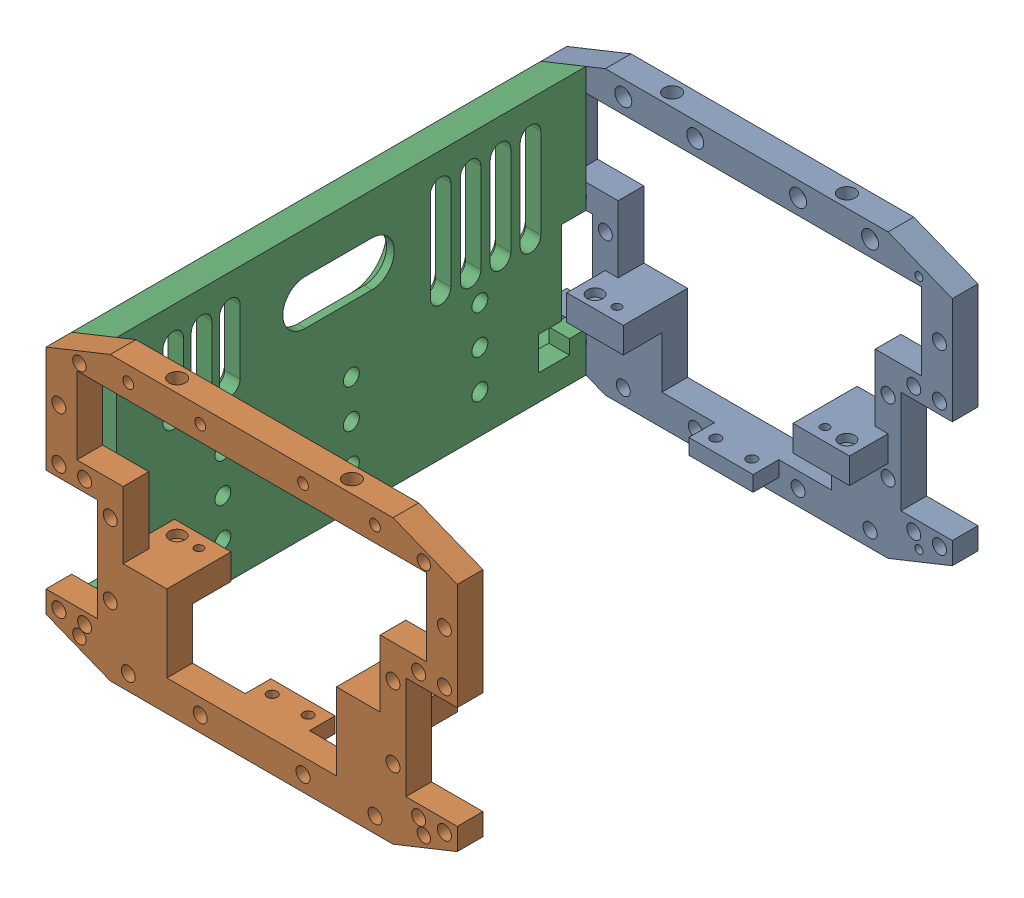
SolidWorks assembly BodyAssembly1, configuration Standard. Lengths in mm.
Overall size (160 110 202.6).
3 component instances, 2 part files, 6 mates.
Components (placement in the parent):
- BodyEnd-1: BodyEnd [Standard] at origin size (160 110 25)
- BodyEnd-2: BodyEnd [Standard] at (12.7503 0 202.6) x (-1 0 0) z (0 0 -1) size (160 110 25)
- SidePanel_Closed-1: SidePanel_Closed [Standard] at (-56.1248 4.9643 10) size (17.5 104 182.6)
Mates (geometry in assembly coordinates):
- Concentric1: concentric: circle of BodyEnd-1; circle of SidePanel_Closed-1
- Concentric2: concentric: circle of BodyEnd-1; circle of SidePanel_Closed-1
- Coincident1: coincident anti-aligned: plane of BodyEnd-1 through (61.3752 -50.0357 10) normal (0 0 1); plane of SidePanel_Closed-1 through (-56.1248 4.9643 10) normal (0 0 -1)
- Concentric3: concentric: circle of BodyEnd-2; circle of SidePanel_Closed-1
- Concentric4: concentric: circle of BodyEnd-2; circle of SidePanel_Closed-1
- Coincident2: coincident anti-aligned: plane of BodyEnd-2 through (-48.6248 -50.0357 192.6) normal (0 0 -1); plane of SidePanel_Closed-1 through (-56.1248 4.9643 192.6) normal (0 0 1)
